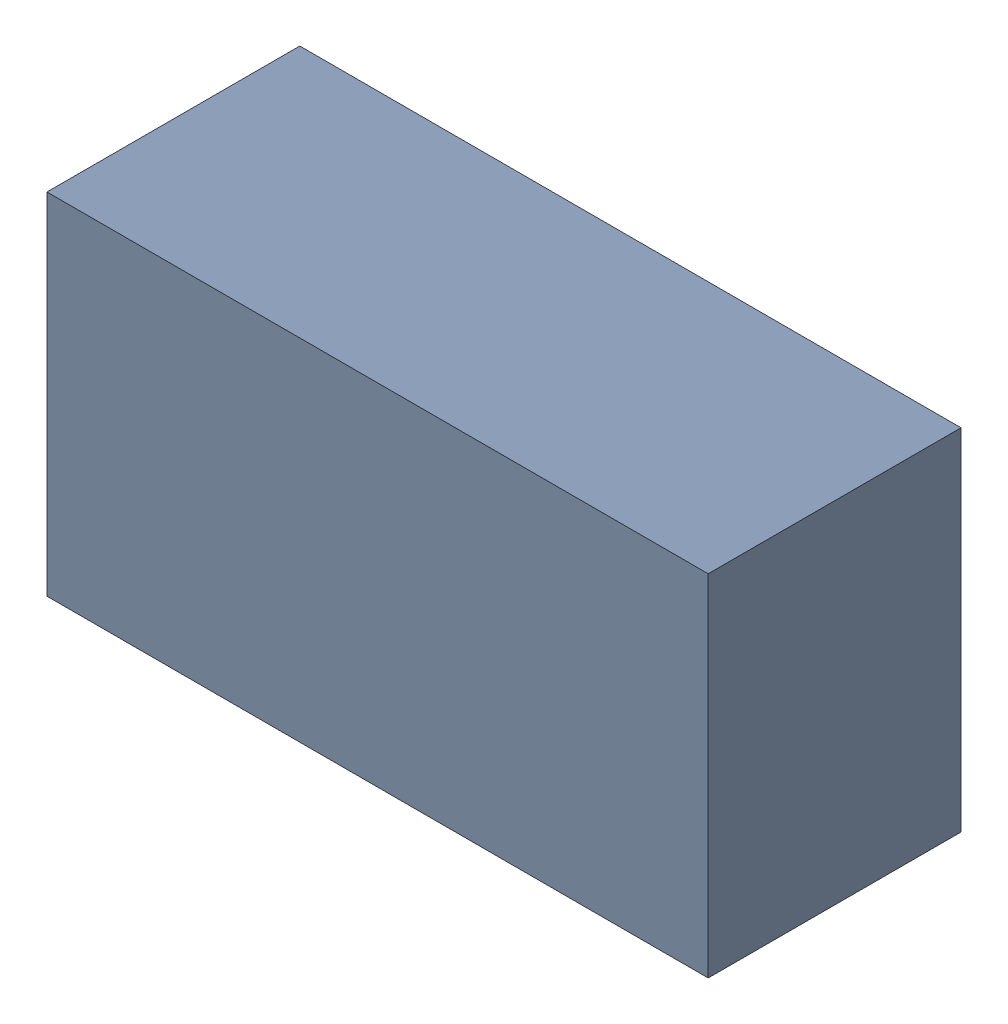
SolidWorks assembly C209, configuration Standard. Lengths in mm.
Overall size (3.4 1.8 1.3).
2 component instances, 1 part files, 0 mates.
Components (placement in the parent):
- 885542104-1: 885542104 [Standard] at (5.8 -22.55 0) size (3.4 1.8 1.3)
  - Extruded_29-1: Extruded_29 [Standard] at origin size (3.4 1.8 1.3)
